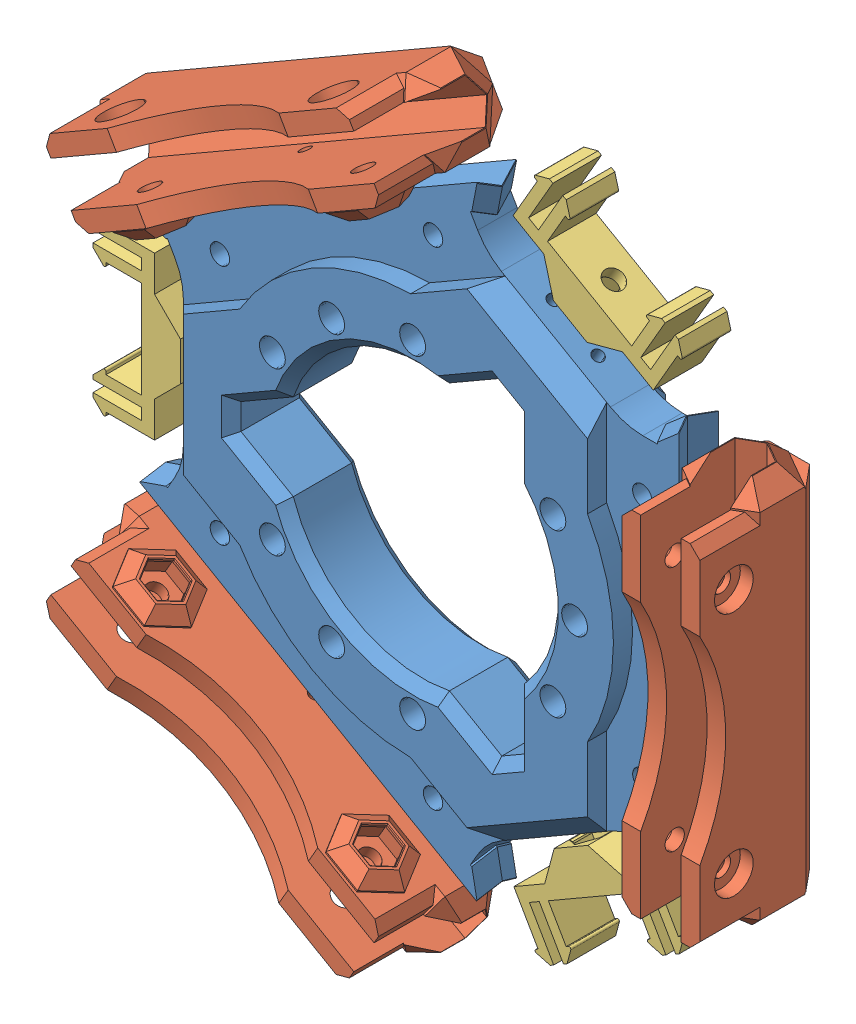
SolidWorks assembly Assem1, configuration Default. Lengths in mm.
Overall size (105.99 120.33 33.79).
7 component instances, 3 part files, 18 mates.
Components (placement in the parent):
- end-effector-1: end-effector [Default] at (0 0 6) x (0 -1 0) z (-1 0 0) size (96.08 12 83.21)
- end-effector-cover-1: end-effector-cover [Default] at (-23.0762 39.9692 47.0725) x (0.866025 0.5 0) z (0 0 1) size (60 14 19.82)
- end-effector-cover-2: end-effector-cover [Default] at (46.1525 0 47.0725) x (0 -1 0) z (0 0 1) size (60 14 19.82)
- end-effector-cover-3: end-effector-cover [Default] at (-23.0762 -39.9692 47.0725) x (-0.866025 0.5 0) z (0 0 1) size (60 14 19.82)
- leveling-bracket-1: leveling-bracket [Default] at (32.9442 57.8627 -144.0353) x (0.612372 -0.353553 -0.707107) z (0.612372 -0.353553 0.707107) size (23.9 13.5 23.9)
- leveling-bracket-2: leveling-bracket [Default] at (33.0716 -57.7892 -144.0353) x (-0.612372 -0.353553 -0.707107) z (-0.612372 -0.353553 0.707107) size (23.9 13.5 23.9)
- leveling-bracket-3: leveling-bracket [Default] at (-66.5827 -0.3279 -144.0353) x (0 0.707107 -0.707107) z (0 0.707107 0.707107) size (23.9 13.5 23.9)
Mates (geometry in assembly coordinates):
- Coincident1: coincident anti-aligned: plane of end-effector-1 through (25 0 0) normal (0 0 -1); plane of assembly through (0 0 0) normal (0 0 1)
- Coincident2: coincident anti-aligned: plane of end-effector-1; plane of assembly through (0 0 0) normal (0 1 0)
- Coincident4: coincident anti-aligned: plane of end-effector-1 through (0 0 6) normal (-1 0 0); plane of assembly through (0 0 0) normal (1 0 0)
- Coincident5: coincident anti-aligned: plane of end-effector-cover-1 through (-4.5714 54.2615 0) normal (0 0 -1); plane of assembly through (0 0 0) normal (0 0 1)
- Distance1: distance = 2 mm: plane of end-effector-cover-1 through (-0.0089 46.359 19.8225) normal (0.5 -0.866025 0); line of end-effector-1 through (-45.057 18.041 9.05) axis (0.866025 0.5 0)
- Coincident7: coincident aligned: plane of end-effector-1 through (25.9808 15 6) normal (0.866025 0.5 0); plane of end-effector-cover-1 through (2.9045 54.9692 47.0725) normal (0.866025 0.5 0)
- Coincident8: coincident anti-aligned: plane of end-effector-cover-3 through (-44.7061 -31.0896 0) normal (0 0 -1); plane of assembly through (0 0 0) normal (0 0 1)
- Distance3: distance = 2 mm: plane of end-effector-cover-3 through (-40.1436 -23.1872 19.8225) normal (0.5 0.866025 0); line of end-effector-1 through (6.9045 -48.041 9.05) axis (-0.866025 0.5 0)
- Coincident12: coincident aligned: plane of end-effector-1 through (25.9808 -15 6) normal (0.866025 -0.5 0); plane of end-effector-cover-3 through (2.9045 -54.9692 47.0725) normal (0.866025 -0.5 0)
- Coincident13: coincident anti-aligned: plane of end-effector-cover-2 through (49.2775 -23.1718 0) normal (0 0 -1); plane of assembly through (0 0 0) normal (0 0 1)
- Distance4: distance = 2 mm: plane of end-effector-cover-2 through (40.1525 -23.1718 19.8225) normal (-1 0 0); line of end-effector-1 through (38.1525 -30 9.05) axis (0 1 0)
- Coincident15: coincident aligned: plane of end-effector-1 through (0 -30 6) normal (0 -1 0); plane of end-effector-cover-2 through (46.1525 -30 47.0725) normal (0 -1 0)
- Coincident16: coincident anti-aligned: plane of leveling-bracket-1 through (31.8461 41.7535 0) normal (0 0 -1); plane of assembly through (0 0 0) normal (0 0 1)
- Distance5: distance = 2 mm anti-aligned: plane of leveling-bracket-1 through (17.2212 36.6295 -14.5602) normal (-0.5 -0.866025 0); plane of end-effector-1 through (38.2688 22.1683 2.95) normal (0.5 0.866025 0)
- Coincident25: coincident aligned: plane of leveling-bracket-1 through (31.8461 41.7535 0) normal (0 0 -1); plane of leveling-bracket-2 through (19.6697 -48.7836 0) normal (0 0 -1)
- Distance6: distance = 2 mm anti-aligned: plane of leveling-bracket-2 through (22.5447 -33.556 -14.5602) normal (-0.5 0.866025 0); plane of end-effector-1 through (0.0639 -44.2259 2.95) normal (0.5 -0.866025 0)
- Coincident27: coincident aligned: plane of leveling-bracket-2 through (19.6697 -48.7836 0) normal (0 0 -1); plane of leveling-bracket-3 through (-52.0827 6.7756 0) normal (0 0 -1)
- Distance7: distance = 2 mm anti-aligned: plane of leveling-bracket-3 through (-40.3327 -3.3279 -14.5602) normal (1 0 0); plane of end-effector-1 through (-38.3327 -22.0576 2.95) normal (-1 0 0)
